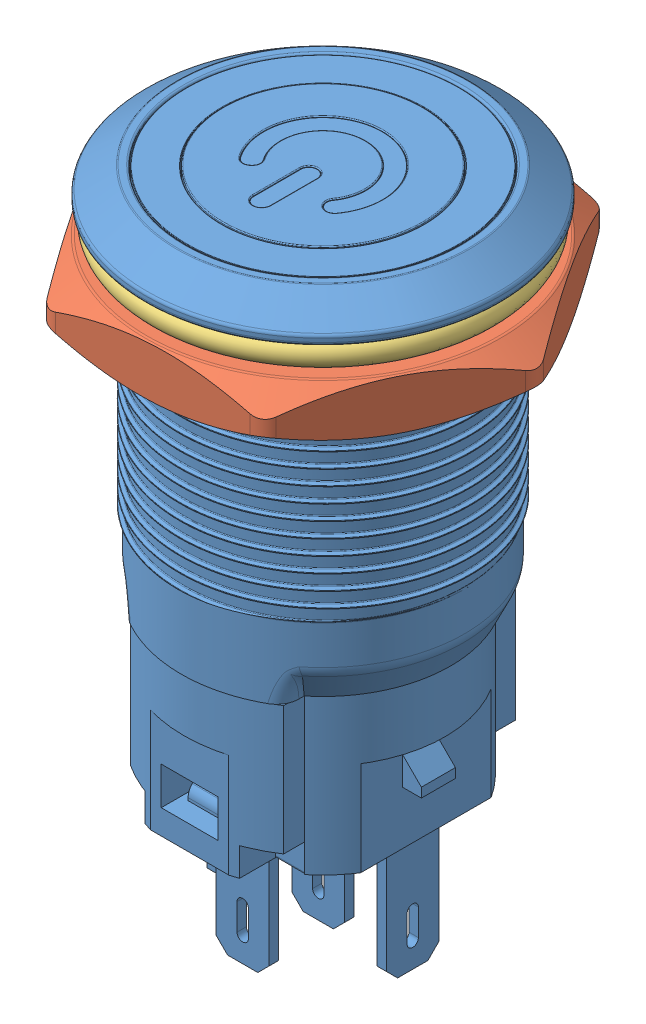
SolidWorks assembly LED_Button_16mm, configuration Default. Lengths in mm.
Overall size (26.77 34.5 27.92).
3 component instances, 3 part files, 3 mates.
Components (placement in the parent):
- Body-1: Body [Default] at origin size (18.8 34.5 18.8)
- Thread-1: Thread [Default] at (0 -4.2912 0) x (0.456141 0 -0.889908) z (0.889908 0 0.456141) size (21.63 2.8 19)
- O-Ring-1: O-Ring [Default] at (0 -0.7221 0) x (0.957514 0 -0.288386) z (0.288386 0 0.957514) size (18.4 1.4 18.4)
Mates (geometry in assembly coordinates):
- Concentric1: concentric aligned: cylinder of Body-1 through (0 -16.3 0) axis (0 1 0) radius 7.5; circle of Thread-1
- LimitDistance1: limit distance = 1.4912 mm anti-aligned: plane of Body-1 through (0 0 0) normal (0 -1 0); plane of Thread-1 through (0 -1.4912 0) normal (0 1 0)
- Concentric2: concentric aligned: line of Body-1; line of O-Ring-1 through (0 -0.7221 0) axis (0 1 0)
